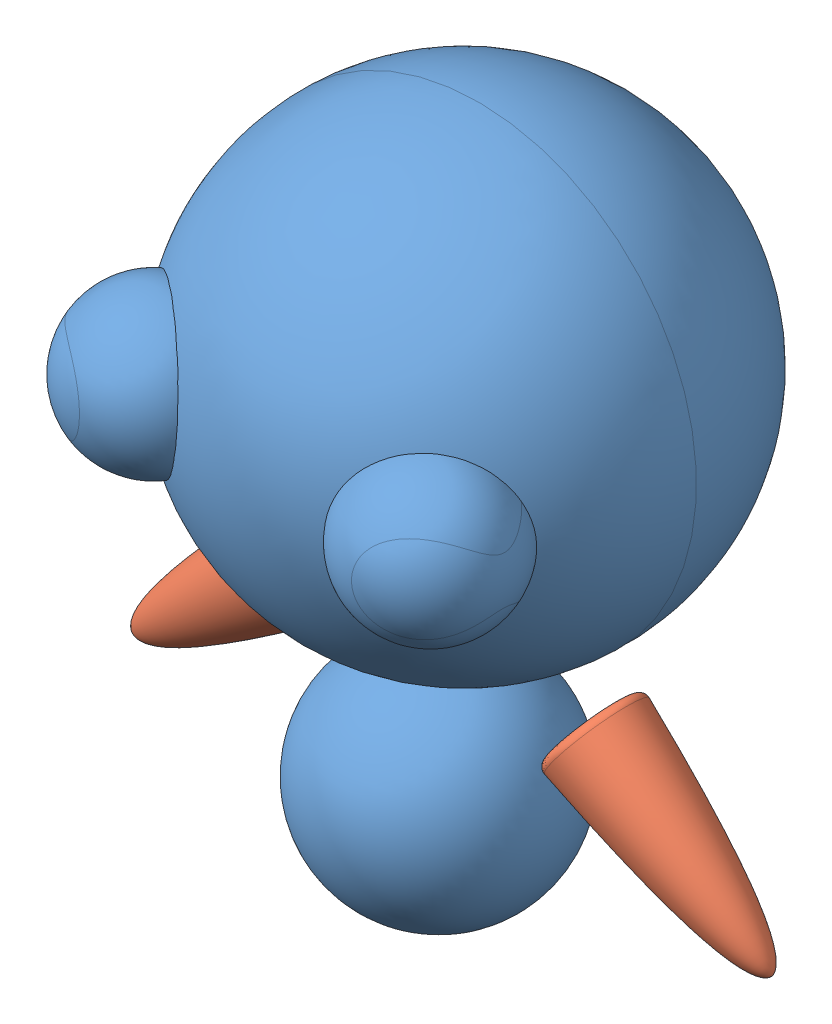
SolidWorks assembly Assemblage2, configuration Défaut. Lengths in mm.
Overall size (161.66 172.39 122.2).
3 component instances, 2 part files, 0 mates.
Components (placement in the parent):
- spectateur-1: spectateur [Défaut] at (-9.724 27.3437 71.5989) x (0.999358 -0.028969 -0.021083) z (0.022321 0.043077 0.998822) size (108.19 164.62 112.86)
- bras-2: bras [Défaut] at (-58.2742 -35.1178 73.2064) x (0.970902 -0.236266 0.039083) z (-0.037767 0.010095 0.999236) size (53.19 50.76 62.48)
- bras-3: bras [Défaut] at (64.59 0.3832 72.2559) x (0.006308 0.99855 0.053453) z (-0.023943 -0.053288 0.998292) size (53.19 50.76 62.48)
